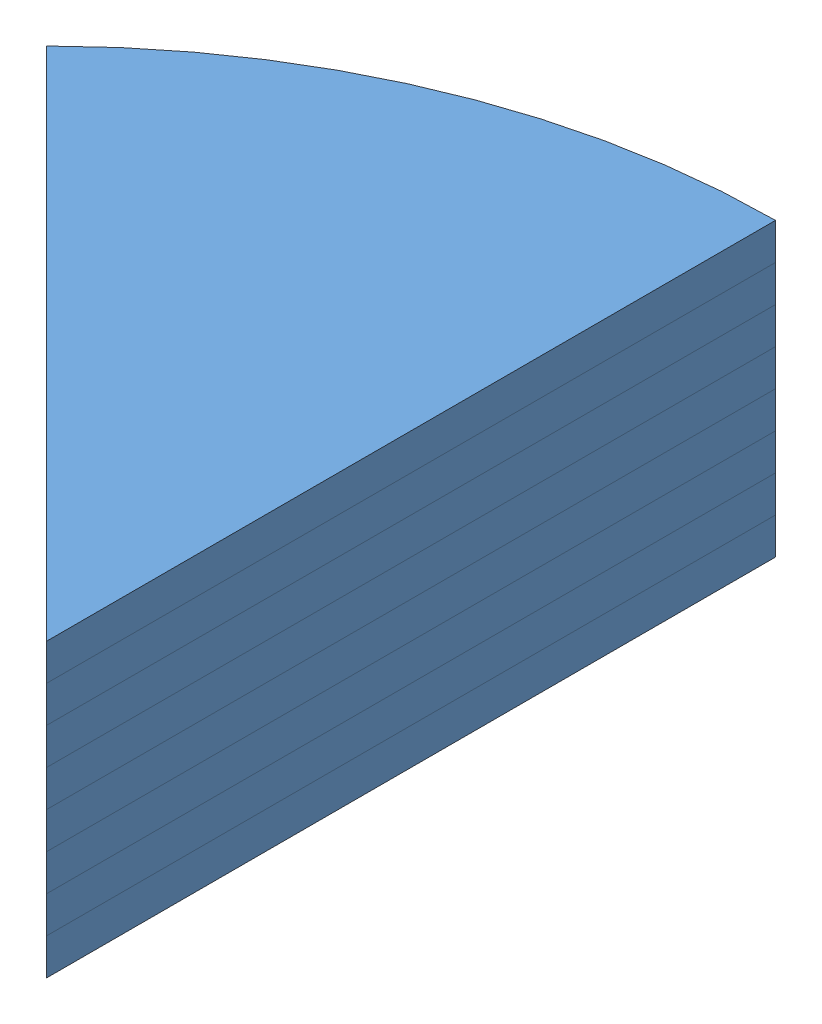
SolidWorks assembly small solar panel, configuration Default. Lengths in mm.
Overall size (282.84 160 400).
8 component instances, 1 part files, 22 mates.
Components (placement in the parent):
- small solar cell-10: small solar cell [Default] at (274.8121 -18.0732 512.7073) size (282.84 20 400)
- small solar cell-11: small solar cell [Default] at (274.8121 -38.0732 512.7073) size (282.84 20 400)
- small solar cell-12: small solar cell [Default] at (274.8121 -58.0732 512.7073) size (282.84 20 400)
- small solar cell-13: small solar cell [Default] at (274.8121 -78.0732 512.7073) size (282.84 20 400)
- small solar cell-14: small solar cell [Default] at (274.8121 21.9268 512.7073) size (282.84 20 400)
- small solar cell-15: small solar cell [Default] at (274.8121 1.9268 512.7073) size (282.84 20 400)
- small solar cell-16: small solar cell [Default] at (274.8121 41.9268 512.7073) size (282.84 20 400)
- small solar cell-17: small solar cell [Default] at (274.8121 61.9268 512.7073) size (282.84 20 400)
Mates (geometry in assembly coordinates):
- Coincident10: coincident: plane of small solar cell-16 through (274.8121 61.9268 512.7073) normal (0 1 0); plane of ? through (274.8121 61.9268 512.7073) normal (0 -1 0)
- Coincident11: coincident anti-aligned: plane of small solar cell-14 through (274.8121 41.9268 512.7073) normal (0 1 0); plane of ? through (274.8121 41.9268 512.7073) normal (0 -1 0)
- Coincident13: coincident anti-aligned: plane of small solar cell-14 through (274.8121 21.9268 512.7073) normal (0 -1 0); plane of small solar cell-15 through (274.8121 21.9268 512.7073) normal (0 1 0)
- Coincident14: coincident anti-aligned: plane of small solar cell-10 through (274.8121 1.9268 512.7073) normal (0 1 0); plane of small solar cell-15 through (274.8121 1.9268 512.7073) normal (0 -1 0)
- Coincident15: coincident anti-aligned: plane of small solar cell-10 through (274.8121 -18.0732 512.7073) normal (0 -1 0); plane of ? through (274.8121 -18.0732 512.7073) normal (0 1 0)
- Coincident16: coincident anti-aligned: plane of ? through (274.8121 -38.0732 512.7073) normal (0 -1 0); plane of ? through (274.8121 -38.0732 512.7073) normal (0 1 0)
- Coincident20: coincident: line of small solar cell-16; line of ?
- Coincident21: coincident aligned: line of small solar cell-14; line of ?
- Coincident22: coincident aligned: line of small solar cell-14; line of small solar cell-15
- Coincident23: coincident aligned: line of small solar cell-10; line of small solar cell-15
- Coincident24: coincident aligned: line of small solar cell-10; line of ?
- Coincident25: coincident aligned: line of ?; line of ?
- Coincident26: coincident anti-aligned: plane of ? through (274.8121 -58.0732 512.7073) normal (0 -1 0); plane of ? through (274.8121 -58.0732 512.7073) normal (0 1 0)
- Coincident28: coincident anti-aligned: plane of ? through (274.8121 -58.0732 512.7073) normal (0 -1 0); plane of ? through (274.8121 -58.0732 512.7073) normal (0 1 0)
- Coincident29: coincident aligned: line of ?; line of ?
- Coincident30: coincident aligned: plane of ? through (274.8121 -38.0732 512.7073) normal (-0.756415 0 0.654093); plane of ? through (274.8121 -58.0732 512.7073) normal (-0.756415 0 0.654093)
- Coincident31: coincident aligned: plane of ? through (274.8121 -18.0732 512.7073) normal (-0.756415 0 0.654093); plane of ? through (274.8121 -38.0732 512.7073) normal (-0.756415 0 0.654093)
- Coincident32: coincident aligned: plane of small solar cell-10 through (274.8121 1.9268 512.7073) normal (-0.707107 0 0.707107); plane of ? through (274.8121 -18.0732 512.7073) normal (-0.756415 0 0.654093)
- Coincident33: coincident aligned: plane of small solar cell-10 through (274.8121 1.9268 512.7073) normal (-0.707107 0 0.707107); plane of small solar cell-15 through (274.8121 21.9268 512.7073) normal (-0.707107 0 0.707107)
- Coincident34: coincident aligned: plane of small solar cell-14 through (274.8121 41.9268 512.7073) normal (-0.707107 0 0.707107); plane of small solar cell-15 through (274.8121 21.9268 512.7073) normal (-0.707107 0 0.707107)
- Coincident35: coincident aligned: plane of small solar cell-14 through (274.8121 41.9268 512.7073) normal (-0.707107 0 0.707107); plane of ? through (274.8121 61.9268 512.7073) normal (-0.337707 0 0.941251)
- Coincident36: coincident aligned: plane of small solar cell-16 through (274.8121 61.9268 512.7073) normal (-0.707107 0 0.707107); plane of ? through (274.8121 81.9268 512.7073) normal (-0.306923 0 0.951734)
